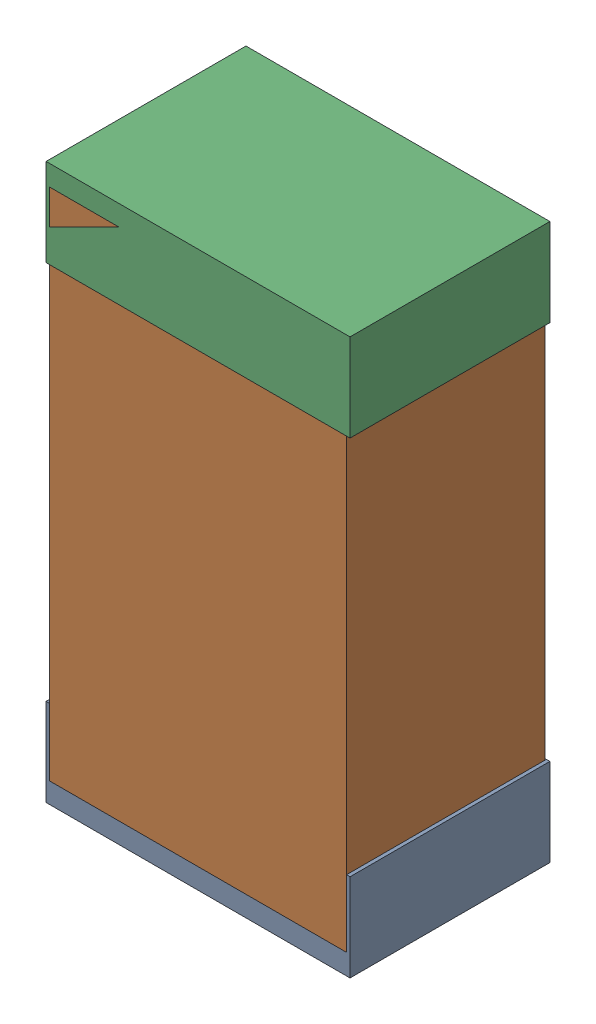
SolidWorks assembly R23Kanaloa_v2.0.0_Motor, configuration Default. Lengths in mm.
Overall size (1.3 2.38 0.85).
6 component instances, 2 part files, 0 mates.
Components (placement in the parent):
- 330415056-1: 330415056 [Default] at (42.418 92.726 -1.9574) size (1.3 0.38 0.85)
  - Extruded_2-1: Extruded_2 [Default] at origin size (1.3 0.38 0.85)
- 334787376-1: 334787376 [Default] at (42.418 93.726 -1.9524) size (1.27 2.2 0.85)
  - Extruded_16-1: Extruded_16 [Default] at origin size (1.27 2.2 0.85)
- 330415056-2: 330415056 [Default] at (42.418 94.726 -1.9574) size (1.3 0.38 0.85)
  - Extruded_2-1: Extruded_2 [Default] at origin size (1.3 0.38 0.85)
